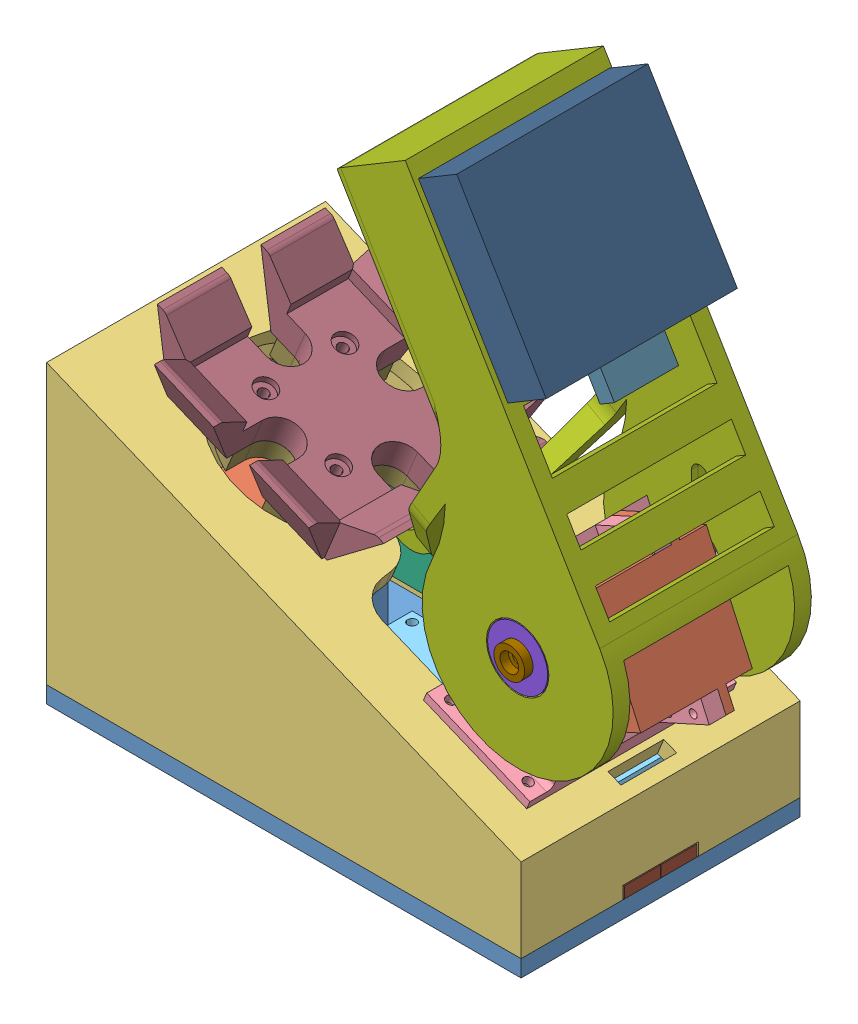
SolidWorks assembly Rubix Cube Solver Assembly, configuration Default. Lengths in mm.
Overall size (203.74 225.82 100).
17 component instances, 15 part files, 41 mates.
Components (placement in the parent):
- Part - Bottom Lid-1: Part - Bottom Lid [Default] at (43.2063 49.0632 144.6054) size (170 69.21 100)
- REFERENCE - Motor-1: REFERENCE - Motor [Default] at (-9.0793 89.0337 155.1154) x (0 0 -1) z (0.924678 -0.38075 0) size (54.8 45.8 20)
- Part - Casing-1: Part - Casing [Default] at (43.2063 55.0632 144.6054) x (0 0 1) z (-1 0 0) size (100 100 172)
- Part - Hinge-1: Part - Hinge [Default] at (98.7398 97.1965 144.6054) x (0 0 1) z (-0.924678 0.38075 0) size (74 58.11 53.7)
- REFERENCE - PI-1: REFERENCE - PI [Default] at (63.0043 55.0632 150.9414) x (-1 0 0) z (0 0 -1) size (90 17.2 55)
- REFERENCE - Connection Board-1: REFERENCE - Connection Board [Default] at (8.0426 91.6937 120.6054) x (1 0 0) z (0 1 0) size (70 20 30)
- REFERENCE - Motor-2: REFERENCE - Motor [Default] at (117.3179 124.2142 158.2054) x (-0.41272 0.910858 0) z (-0.910858 -0.41272 0) size (54.8 45.8 20)
- Part - Top Arm-1: Part - Top Arm [Default] at (90.593 226.3615 145.1054) x (0 0 -1) z (-0.512766 0.858528 0) size (71 106.31 178.15)
- REFERENCE - Ball Bearing-1: REFERENCE - Ball Bearing [Default] at (112.9843 133.7782 173.6054) x (0.091689 -0.995788 0) z (-0.995788 -0.091689 0) size (21.5 7 21.5)
- Part - Hinge - Screw-1: Part - Hinge - Screw [Default] at (112.9843 133.7782 168.6054) x (-0.954108 -0.299463 0) z (-0.299463 0.954108 0) size (11 15 11)
- Part - Top Arm - Camera Housing-1: Part - Top Arm - Camera Housing [Default] at (93.2489 233.6159 144.6154) x (0 0 -1) z (0.512766 -0.858528 0) size (68.5 16 62.5)
- REFERENCE - Charging Board-1: REFERENCE - Charging Board [Default] at (121.2063 55.0632 138.0054) size (14 4.36 13)
- REFERENCE - Charging Board-2: REFERENCE - Charging Board [Default] at (121.2063 55.0632 151.1054) size (14 4.36 13)
- Part - Rotary Disk-1: Part - Rotary Disk [Default] at (7.5214 129.3497 144.6154) x (0.652134 -0.268526 0.708953) z (-0.655554 0.269934 0.705255) size (59 7 59)
- Part - Cube Holder-1: Part - Cube Holder [Default] at (10.1866 135.8224 144.6154) x (-0.924675 0.380749 -0.002615) z (0.002418 -0.000996 -0.999997) size (88 46.28 88)
- REFERENCE - LED-1: REFERENCE - LED [Default] at (114.4226 217.6667 143.5662) x (0 0 1) z (0.512766 -0.858528 0) size (23 8 30)
- REFERENCE - Pi Camera-1: REFERENCE - Pi Camera [Default] at (100.6292 240.7611 143.7919) x (0 0 -1) z (-0.512766 0.858528 0) size (25 9 23.8)
Mates (geometry in assembly coordinates):
- Coincident1: coincident anti-aligned: plane of Part - Bottom Lid-1 through (-4.8041 87.2733 182.6054) normal (0.38075 0.924678 0); plane of REFERENCE - Motor-1 through (-9.0793 89.0337 155.1154) normal (-0.38075 -0.924678 0)
- Coincident2: coincident anti-aligned: plane of Part - Bottom Lid-1 through (43.2063 55.0632 144.6054) normal (0 1 0); plane of Part - Casing-1 through (-41.7937 55.0632 194.6054) normal (0 -1 0)
- Coincident3: coincident aligned: plane of Part - Bottom Lid-1 through (-41.7937 55.0632 194.6054) normal (-1 0 0); plane of Part - Casing-1 through (-41.7937 55.0632 194.6054) normal (-1 0 0)
- Coincident4: coincident aligned: plane of Part - Bottom Lid-1 through (-41.7937 55.0632 194.6054) normal (0 0 1); plane of Part - Casing-1 through (43.2063 55.0632 194.6054) normal (0 0 1)
- Coincident5: coincident anti-aligned: plane of Part - Bottom Lid-1 through (0.1675 85.2262 182.6054) normal (-0.924678 0.38075 0); plane of REFERENCE - Motor-1 through (15.3975 122.2133 175.1154) normal (0.924678 -0.38075 0)
- Concentric1: concentric anti-aligned: circle of Part - Bottom Lid-1; circle of REFERENCE - Motor-1
- Coincident8: coincident anti-aligned: plane of Part - Casing-1 through (-41.7937 155.0632 194.6054) normal (0.38075 0.924678 0); plane of Part - Hinge-1 through (98.7398 97.1965 144.6054) normal (-0.38075 -0.924678 0)
- Coincident9: coincident anti-aligned: plane of Part - Bottom Lid-1 through (43.2063 55.0632 144.6054) normal (0 1 0); plane of REFERENCE - PI-1 through (63.0043 55.0632 150.9414) normal (0 -1 0)
- Concentric2: concentric aligned: circle of Part - Bottom Lid-1; circle of REFERENCE - PI-1
- Concentric3: concentric aligned: circle of Part - Bottom Lid-1; circle of REFERENCE - PI-1
- Coincident14: coincident anti-aligned: plane of Part - Casing-1 through (43.2063 55.0632 100.6054) normal (0 0 1); plane of REFERENCE - Connection Board-1 through (8.0426 91.6937 100.6054) normal (0 0 -1)
- Concentric4: concentric aligned: circle of Part - Casing-1; circle of REFERENCE - Connection Board-1
- Concentric5: concentric aligned: circle of Part - Casing-1; circle of REFERENCE - Connection Board-1
- Concentric6: concentric aligned: circle of Part - Hinge-1; circle of Part - Casing-1
- Concentric7: concentric aligned: circle of Part - Casing-1; circle of Part - Hinge-1
- Coincident20: coincident anti-aligned: plane of Part - Hinge-1 through (119.5178 95.1295 160.2054) normal (0.910858 0.41272 0); plane of REFERENCE - Motor-2 through (116.4637 101.8699 118.2054) normal (-0.910858 -0.41272 0)
- Concentric8: concentric aligned: circle of Part - Hinge-1; circle of REFERENCE - Motor-2
- Coincident22: coincident anti-aligned: plane of Part - Hinge-1 through (137.735 103.3839 130.7054) normal (0 0 -1); plane of REFERENCE - Motor-2 through (119.5178 95.1295 130.7054) normal (0 0 1)
- Concentric9: concentric aligned: circle of Part - Hinge-1; circle of Part - Top Arm-1
- Concentric11: concentric anti-aligned: cylinder of Part - Top Arm-1 through (112.9843 133.7782 170.6054) axis (0 0 1) radius 11.2; cylinder of REFERENCE - Ball Bearing-1 through (112.9843 133.7782 180.6054) axis (0 0 -1) radius 10.75
- Coincident23: coincident aligned: plane of Part - Top Arm-1 through (48.307 246.4559 180.6054) normal (0 0 1); plane of REFERENCE - Ball Bearing-1 through (112.9843 133.7782 180.6054) normal (0 0 1)
- Concentric13: concentric aligned: circle of REFERENCE - Ball Bearing-1; circle of Part - Hinge - Screw-1
- Coincident26: coincident anti-aligned: plane of Part - Hinge-1 through (112.9843 133.7782 168.6054) normal (0 0 1); plane of Part - Hinge - Screw-1 through (112.9843 133.7782 168.6054) normal (0 0 -1)
- Coincident27: coincident anti-aligned: plane of Part - Top Arm-1 through (48.307 246.4559 180.6054) normal (0 0 1); plane of Part - Hinge - Screw-1 through (112.9843 133.7782 180.6054) normal (0 0 -1)
- Coincident30: coincident aligned: line of Part - Top Arm-1 through (78.7633 257.8693 116.3654) axis (0 0 1); line of Part - Top Arm - Camera Housing-1 through (78.7633 257.8693 116.3654) axis (0 0 1)
- Coincident31: coincident aligned: line of Part - Top Arm-1 through (107.7346 209.3625 116.3654) axis (-0.512766 0.858528 0); line of Part - Top Arm - Camera Housing-1 through (107.7346 209.3625 116.3654) axis (-0.512766 0.858528 0)
- Coincident32: coincident anti-aligned: plane of Part - Bottom Lid-1 through (43.2063 55.0632 144.6054) normal (0 1 0); plane of REFERENCE - Charging Board-2 through (121.2063 55.0632 151.1054) normal (0 -1 0)
- Coincident33: coincident anti-aligned: plane of Part - Bottom Lid-1 through (43.2063 55.0632 144.6054) normal (0 1 0); plane of REFERENCE - Charging Board-1 through (121.2063 55.0632 138.0054) normal (0 -1 0)
- Concentric14: concentric aligned: circle of Part - Bottom Lid-1; circle of REFERENCE - Charging Board-1
- Concentric15: concentric aligned: circle of Part - Bottom Lid-1; circle of REFERENCE - Charging Board-2
- Concentric16: concentric aligned: circle of Part - Bottom Lid-1; circle of REFERENCE - Charging Board-2
- Concentric17: concentric aligned: circle of Part - Bottom Lid-1; circle of REFERENCE - Charging Board-1
- Concentric18: concentric aligned: circle of REFERENCE - Motor-1; circle of Part - Rotary Disk-1
- Concentric19: concentric aligned: circle of Part - Rotary Disk-1; circle of Part - Cube Holder-1
- Concentric20: concentric anti-aligned: circle of Part - Rotary Disk-1; circle of Part - Cube Holder-1
- Coincident40: coincident anti-aligned: plane of Part - Rotary Disk-1 through (10.1866 135.8224 144.6154) normal (0.38075 0.924678 0); plane of Part - Cube Holder-1 through (10.1866 135.8224 144.6154) normal (-0.38075 -0.924678 0)
- Distance1: distance = 2 mm anti-aligned: plane of Part - Cube Holder-1 through (10.1866 135.8224 144.6154) normal (-0.38075 -0.924678 0); plane of Part - Casing-1 through (-41.7937 155.0632 194.6054) normal (0.38075 0.924678 0)
- Coincident42: coincident anti-aligned: plane of Part - Top Arm - Camera Housing-1 through (101.8342 238.7436 144.6154) normal (-0.858528 -0.512766 0); plane of REFERENCE - LED-1 through (114.4226 217.6667 143.5662) normal (0.858528 0.512766 0)
- Coincident44: coincident anti-aligned: plane of Part - Top Arm - Camera Housing-1 through (101.8342 238.7436 144.6154) normal (-0.858528 -0.512766 0); plane of REFERENCE - Pi Camera-1 through (100.6292 240.7611 143.7919) normal (0.858528 0.512766 0)
- Coincident45: coincident anti-aligned: plane of REFERENCE - LED-1 through (101.58 227.468 132.0662) normal (-0.512766 0.858528 0); plane of REFERENCE - Pi Camera-1 through (103.7263 228.7499 156.2919) normal (0.512766 -0.858528 0)
- Distance2: distance = 14 mm anti-aligned: plane of REFERENCE - Pi Camera-1 through (91.5225 249.1829 156.2919) normal (-0.512766 0.858528 0); plane of Part - Top Arm - Camera Housing-1 through (87.3486 262.997 172.8654) normal (0.512766 -0.858528 0)
